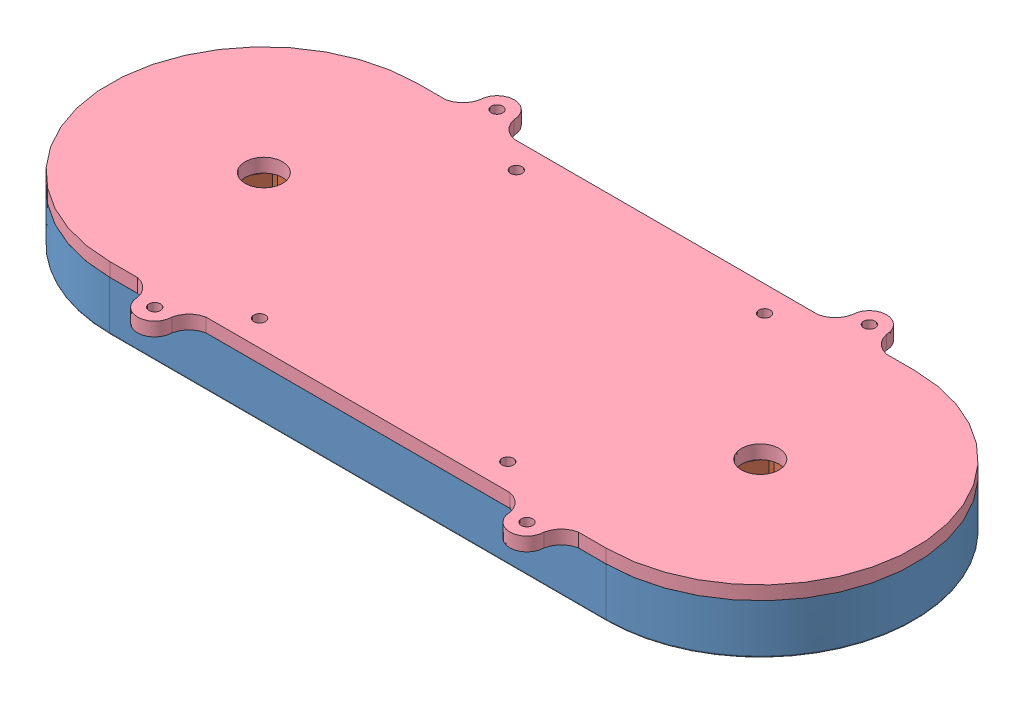
SolidWorks assembly gearbox_subassem, configuration Default. Lengths in mm.
Overall size (235 35 110).
6 component instances, 5 part files, 11 mates.
Components (placement in the parent):
- gearbox_cover-1: gearbox_cover [Default] at (18.0302 85.5802 199.1488) size (235 14.5 90)
- nut_gear-1: nut_gear [Default] at (18.0302 98.0802 199.1488) x (1 0 0) z (0 -1 0) size (77.36 77.46 10)
- nut_gear-2: nut_gear [Default] at (163.0302 98.0802 199.1488) x (1 0 0) z (0 -1 0) size (77.36 77.46 10)
- center_gear-1: center_gear [Default] at (90.5348 97.0802 199.1366) x (0.004395 0 -0.99999) z (0 -1 0) size (77.36 77.46 11)
- gearbox_back_cover-1: gearbox_back_cover [Default] at (18.0348 100.0802 199.1366) size (235 4 110)
- center_key-1: center_key [Default] at (90.5379 69.0802 198.4236) x (0.05807 0 -0.998313) z (0.998313 0 0.05807) size (30 25 30)
Mates (geometry in assembly coordinates):
- Concentric1: concentric aligned: circle of gearbox_cover-1; circle of nut_gear-1
- Concentric2: concentric aligned: circle of gearbox_cover-1; circle of nut_gear-2
- Coincident1: coincident anti-aligned: plane of gearbox_cover-1 through (163.0302 88.0802 199.1488) normal (0 1 0); plane of nut_gear-1 through (18.0302 88.0802 199.1488) normal (0 -1 0)
- Coincident2: coincident anti-aligned: plane of gearbox_cover-1 through (163.0302 88.0802 199.1488) normal (0 1 0); plane of nut_gear-2 through (163.0302 88.0802 199.1488) normal (0 -1 0)
- Concentric4: concentric anti-aligned: circle of gearbox_cover-1; circle of gearbox_back_cover-1
- Parallel1: parallel aligned: line of gearbox_cover-1 through (18.0302 100.0802 244.1488) axis (1 0 0); line of gearbox_back_cover-1 through (46.1598 104.0802 244.1366) axis (1 0 0)
- Coincident4: coincident anti-aligned: plane of gearbox_cover-1 through (18.0302 100.0802 199.1488) normal (0 1 0); plane of gearbox_back_cover-1 through (18.0348 100.0802 199.1366) normal (0 -1 0)
- Coincident9: coincident: point of center_gear-1; point of gearbox_back_cover-1
- Parallel3: parallel aligned: plane of center_gear-1 through (90.5348 91.0802 199.1366) normal (0 -1 0); plane of gearbox_back_cover-1 through (18.0348 100.0802 199.1366) normal (0 -1 0)
- Concentric7: concentric anti-aligned: circle of center_gear-1; circle of center_key-1
- Coincident15: coincident anti-aligned: plane of center_gear-1 through (90.5379 94.0802 198.4236) normal (0 -1 0); plane of center_key-1 through (90.5379 94.0802 198.4236) normal (0 1 0)
